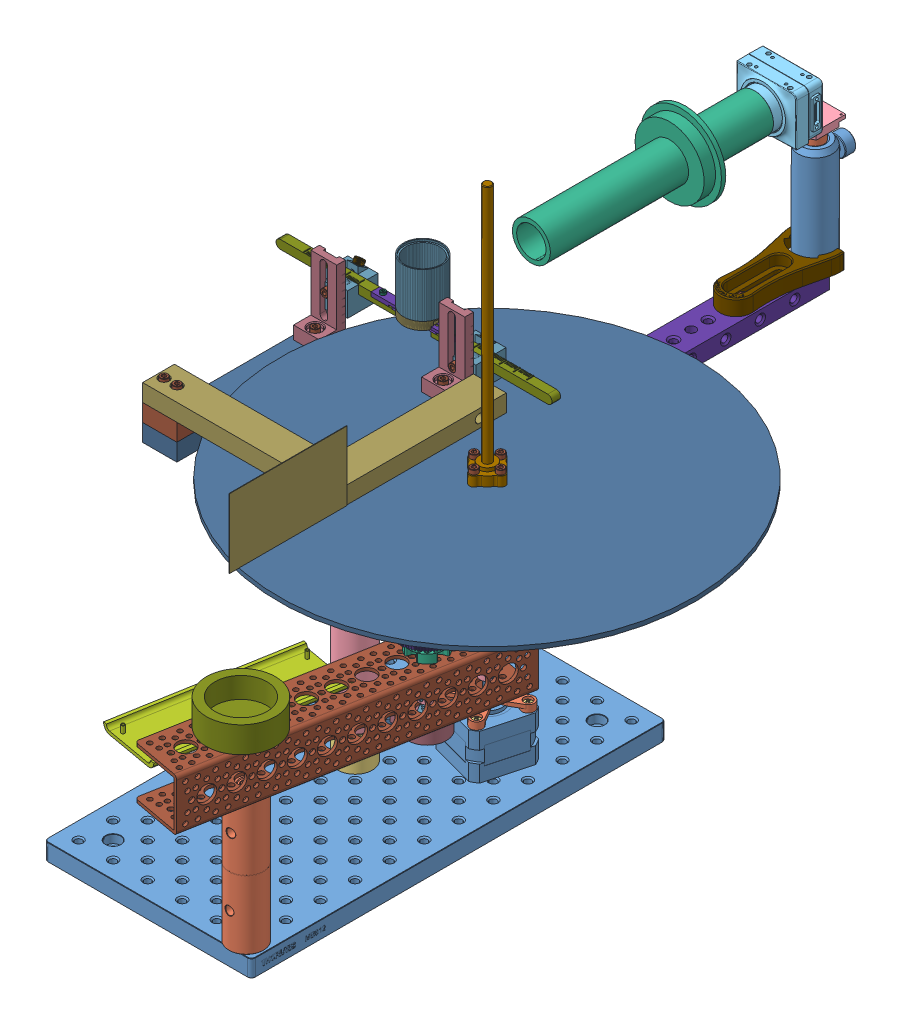
SolidWorks assembly Treadmill Rig, configuration Default. Lengths in mm.
Overall size (431.05 433.26 578.18).
98 component instances, 51 part files, 81 mates.
Components (placement in the parent):
- THORLABS_baseplate_MB612-1: THORLABS_baseplate_MB612 [Default] at (-0.1242 -6.1137 192.459) x (0 0 -1) z (1 0 0) size (304.8 12.7 152.4)
- THORLABS_RS2-1: THORLABS_RS2 [Default] at (59.6783 32.9835 335.1367) size (25.37 50.8 25.57)
- THORLABS_RS2-2: THORLABS_RS2 [Default] at (59.7309 82.7675 335.3233) x (0.99667 0 -0.081541) z (0.081541 0 0.99667) size (25.37 50.8 25.57)
- THORLABS_leg_RS1-1: THORLABS_leg_RS1 [Default] at (-12.6817 22.1402 176.1265) x (0.014723 0 0.999892) z (-0.999892 0 0.014723) size (25.57 25.4 25.37)
- THORLABS_leg_RS1-2: THORLABS_leg_RS1 [Default] at (-64.1349 22.3942 132.5582) x (0.086893 0 -0.996218) z (0.996218 0 0.086893) size (25.57 25.4 25.37)
- THORLABS_leg_RS6-1: THORLABS_leg_RS6 [Default] at (-12.2453 109.5652 178.3441) size (25.37 152.4 25.57)
- THORLABS_leg_RS6-2: THORLABS_leg_RS6 [Default] at (-63.0453 109.8192 127.5441) size (25.37 152.4 25.57)
- gonio_platform-1: gonio_platform [Default] at (-38.5742 174.1917 156.509) x (0 0 -1) z (1 0 0) size (97.5 10 97.5)
- GOH-40A35RUU-1: GOH-40A35RUU [Default] at (-4.8242 205.9417 127.759) x (-1 0 0) z (0 1 0) size (50.47 46.7 16)
  - GOH40A35RUU-M02-13001-S02-1: GOH40A35RUU-M02-13001-S02 [Default] at origin size (50 40 13.5)
  - GOH40A35RUU-M02-13001-S01-1: GOH40A35RUU-M02-13001-S01 [Default] at origin size (40.85 46.7 14)
- GOH-40A51UU-1: GOH-40A51UU [Default] at (-9.8242 133.1917 127.759) x (0 0 -1) z (0 -1 0) size (50.27 46.7 15)
  - GOH-8UU-C1B-S02-1: GOH-8UU-C1B-S02 [Default] at origin size (50 40 12.5)
  - GOH-8UU-C1B-S01-1: GOH-8UU-C1B-S01 [Default] x (0 1 0) z (0 0 1) size (46.7 40.57 13)
- headbar platform-1: headbar platform [Default] at (-72.0542 215.1917 200.699) size (93.98 12.7 156.21)
- Cap spacer-1: Cap spacer [Default] at (-72.0542 227.8917 252.769) size (25.4 12.7 22.86)
- headbar platform 2-1: headbar platform 2 [Default] at (-8.3145 240.5917 253.531) x (0 0 1) z (-1 0 0) size (127 12.7 140.21)
- headbar_post-1: headbar_post [Default] at (-81.5792 227.8917 156.249) x (0 0 -1) z (1 0 0) size (19.05 50.8 19.07)
- headbar_post-2: headbar_post [Default] at (12.5135 241.8617 156.249) x (0 0 -1) z (1 0 0) size (19.05 50.8 19.07)
- headbar finished flipped (1)-1: headbar finished flipped (1) [Default] at (-60.8105 251.2717 126.0865) x (-1 0 0) z (0 0 -1) size (88.9 24.86 25.74)
  - bar rest-1: bar rest [Default] at origin size (22.23 22.61 24.77)
  - 91292A003_TYPE 18-8 SS SOCKET HEAD CAP SCREW-1: 91292A003_TYPE 18-8 SS SOCKET HEAD CAP SCREW [91292A003] at (-14.8888 5.7455 0) x (1 0 0) z (0 -1 0) size (3.8 3.8 5.09)
  - headbar-1: headbar [Default] at (-76.8022 -57.3797 49.0764) x (0 0 -1) z (1 0 0) size (6.4 6.86 88.9)
    - headpost holder-1: headpost holder [Default] at (49.0764 62.9677 48.5529) x (0 1 0) z (0 0 1) size (6.86 6.35 88.9)
    - headbar clamp-1: headbar clamp [Default] at (49.0764 64.2202 58.1033) x (0 0 1) z (-1 0 0) size (19.1 3.05 6.4)
  - 96125A301_NICKEL ALLOY SHOULDER SCREW-1: 96125A301_NICKEL ALLOY SHOULDER SCREW [96125A301] at (10.7798 13.9746 8.8593) x (0.978373 0.111501 -0.174221) z (0 0.842271 0.539054) size (6.35 6.35 10.69)
- headbar finished assem (1)-1: headbar finished assem (1) [Default] at (33.2821 251.0177 126.0865) x (-1 0 0) z (0 0 -1) size (88.9 24.55 25.25)
  - bar rest-1: bar rest [Default] at origin size (22.23 22.61 24.77)
  - 91292A003_TYPE 18-8 SS SOCKET HEAD CAP SCREW-1: 91292A003_TYPE 18-8 SS SOCKET HEAD CAP SCREW [91292A003] at (27.4332 5.7455 0) x (1 0 0) z (0 -1 0) size (3.8 3.8 5.09)
  - headbar-1: headbar [Default] at (89.3465 -57.3797 -49.0764) x (0 0 1) z (-1 0 0) size (6.4 6.86 88.9)
    - headpost holder-1: headpost holder [Default] at (49.0764 62.9677 48.5529) x (0 1 0) z (0 0 1) size (6.86 6.35 88.9)
    - headbar clamp-1: headbar clamp [Default] at (49.0764 64.2202 58.1033) x (0 0 1) z (-1 0 0) size (19.1 3.05 6.4)
  - 96125A301_NICKEL ALLOY SHOULDER SCREW-1: 96125A301_NICKEL ALLOY SHOULDER SCREW [96125A301] at (10.7798 13.9746 8.8593) x (1 0 0) z (0 0.842271 0.539054) size (6.35 6.35 10.69)
- Round Screw Plate (1)-2: Round Screw Plate (1) [Default] at (63.3758 107.2225 332.159) size (25.39 5.58 25.39) (hidden)
- 6-32 Screw-1: 6-32 Screw [Default] at (63.3758 102.3127 332.159) x (0 0 1) z (0 -1 0) size (5.74 5.74 13.19) (hidden)
- Stepper Motor assem-1: Stepper Motor assem [Default] at (89.2983 64.2757 184.6539) x (0.258819 0 -0.965926) z (0.965926 0 0.258819) size (46.31 68.68 42)
  - Stepper Motor 9328-1: Stepper Motor 9328 [Default] at origin size (46.31 57.25 42)
  - 555152 assembly-1: 555152 assembly [Default] at (-46.3202 49.2232 -16.8805) x (-1 0 0) z (0 0 1) size (40.13 13.81 40.13)
    - 555152-1: 555152 [Default] at (-46.3202 6.3172 16.8805) size (40.13 10.02 40.13)
    - 555152 screw_92005A116-1: 555152 screw_92005A116 [Default] at (-61.8202 19.9372 32.3805) x (1 0 0) z (0 -1 0) size (6 6 8.48)
    - 555152 screw_92005A116-2: 555152 screw_92005A116 [Default] at (-30.8202 19.9372 32.3805) x (0 0 -1) z (0 -1 0) size (6 6 8.48)
    - 555152 screw_92005A116-3: 555152 screw_92005A116 [Default] at (-30.8202 19.9372 1.3805) x (-1 0 0) z (0 -1 0) size (6 6 8.48)
    - 555152 screw_92005A116-4: 555152 screw_92005A116 [Default] at (-61.8202 19.9372 1.3805) x (0 0 1) z (0 -1 0) size (6 6 8.48)
  - Motor coupler-1: Motor coupler [Default] at (-58.4931 67.3592 -25.2523) x (-1 0 0) z (0 0 1) size (10.67 19.11 10.81)
    - 625120-1: 625120 [Default] at (-58.4931 -1.3175 25.2523) size (10.67 19.05 10.73)
    - 632134_91375A436-1: 632134_91375A436 [Default] at (-58.4931 14.3035 29.3961) x (0.606109 -0.795381 0) z (0 0 1) size (4.98 4.83 3.31)
    - 632134_91375A436-2: 632134_91375A436 [Default] at (-58.4931 2.1115 29.3961) x (0.605824 -0.795599 0) z (0 0 1) size (4.98 4.83 3.31)
- Dual Ball Bearing Hub-1: Dual Ball Bearing Hub [Default] at (119.3156 154.9729 164.5547) size (25.4 12.82 25.4)
  - 545444-1: 545444 [Default] at (-30.0172 -12.6196 20.0992) size (25.4 12.82 25.4)
  - 535020-1: 535020 [Default] at (-30.0172 -2.3009 20.0992) size (12.7 4.76 12.7)
  - 535020-2: 535020 [Default] at (-30.0172 -10.2384 20.0992) x (-0.612569 0 0.790417) z (-0.790417 0 -0.612569) size (12.7 4.76 12.7)
- Dual Ball Bearing Hub-2: Dual Ball Bearing Hub [Default] at (112.4883 158.1291 202.038) size (25.4 12.82 25.4)
  - 545444-1: 545444 [Default] at (-30.0172 -12.6196 20.0992) size (25.4 12.82 25.4)
  - 535020-1: 535020 [Default] at (-30.0172 -2.3009 20.0992) size (12.7 4.76 12.7)
  - 535020-2: 535020 [Default] at (-30.0172 -10.2384 20.0992) x (-0.612569 0 0.790417) z (-0.790417 0 -0.612569) size (12.7 4.76 12.7)
- 48 Pitch 72T Gear-1: 48 Pitch 72T Gear [Default] at (89.2983 155.0533 184.6539) x (1 0 0) z (0 1 0) size (39.16 39.16 9.53)
- 48 Pitch 72T Gear-2: 48 Pitch 72T Gear [Default] at (82.471 158.2094 222.1372) x (1 0 0) z (0 1 0) size (39.16 39.16 9.53)
- 12in shaft sldprt-2: 12in shaft sldprt [Default] at (89.2983 122.3502 184.6539) size (6.34 304.8 6.34)
- Track-1: Track [Default] at (89.5764 237.3058 185.33) x (-0.707107 0 -0.707107) z (0.707107 0 -0.707107) size (304.8 3.17 304.8)
- Aluminum Channel 585450-4: Aluminum Channel 585450 [Default] at (111.4536 107.1817 169.3259) x (0 1 0) z (-0.179194 0 0.983814) size (38.1 38.1 228.6)
- plastic sheet-1: plastic sheet [Default] at (56.0745 265.7822 297.7239) x (0 0 1) z (-1 0 0) size (86.36 50.8 0.76)
- Encoder-1: Encoder [Default] at (67.0944 107.1817 222.1372) x (0 0 -1) z (0 -1 0) size (28.19 32.65 25.88)
  - encoder body-1: encoder body [Default] at origin size (28.19 32.65 12.29)
  - 92620A401_HIGH-STRENGTH GRADE 8 STEEL CAP SCREW-1: 92620A401_HIGH-STRENGTH GRADE 8 STEEL CAP SCREW [92620A401] at (0.0022 15.3756 -3.9688) x (0 0 -1) z (1 0 0) size (16.31 11 9.53)
- Motor coupler-1: Motor coupler [Default] at (140.9641 115.6246 196.8849) size (10.67 19.11 10.81)
  - 625120-1: 625120 [Default] at (-58.4931 -1.3175 25.2523) size (10.67 19.05 10.73)
  - 632134_91375A436-1: 632134_91375A436 [Default] at (-58.4931 14.3035 29.3961) x (0.606109 -0.795381 0) z (0 0 1) size (4.98 4.83 3.31)
  - 632134_91375A436-2: 632134_91375A436 [Default] at (-58.4931 2.1115 29.3961) x (0.605824 -0.795599 0) z (0 0 1) size (4.98 4.83 3.31)
- 2in shaft sldprt-1: 2in shaft sldprt [Default] at (82.471 127.4545 222.1372) size (6.34 50.8 6.34)
- weighing dish-1: weighing dish [Default] at (62.5051 145.2817 338.978) size (50.8 19.05 50.8)
- horizontal support 12in-1: horizontal support 12in [Default] at (-8.8742 148.3921 0.2787) x (0 0 -1) z (1 0 0) size (304.8 12.7 25.4)
- CF125-Solidworks-1: CF125-Solidworks [Default] at (-8.8742 166.8071 -154.411) size (36.32 12.6 73.79)
- PH3-Solidworks-2: PH3-Solidworks [Default] at (-8.8742 199.1921 -154.411) x (-1 0 0) z (0 0 -1) size (25 76.81 35.41)
- 0.5in shaft-1: 0.5in shaft [Default] at (-8.8742 168.4097 -154.411) size (12.69 76.2 12.69)
- 90322A645_HIGH-STRENGTH STEEL THREADED ROD-1: 90322A645_HIGH-STRENGTH STEEL THREADED ROD [90322A645] at (-8.8742 239.8472 -154.411) x (0 1 0) z (0 0 1) size (26.4 6.43 6.7)
- camera adapter-3: camera adapter [Default] at (-8.8742 250.3247 -154.411) x (0 0 1) z (1 0 0) size (26.9 5.71 17.9)
- cm3-u3-13y3m-cs camera-2: cm3-u3-13y3m-cs camera [Default] at (-16.4673 268.3484 -131.7476) size (45.85 36.05 28.67)
- 20x lense body-1: 20x lense body [Default] at (-16.4673 268.3484 -117.3347) size (59.44 59.44 163.96)
- electronics tray-1: electronics tray [Default] at (64.2218 135.5171 263.4225) x (0.984808 0 0.173648) z (-0.173648 0 0.984808) size (45.53 7.48 127)
- visual cortex headpost-4: visual cortex headpost [Default] at (-58.3763 256.6582 107.5862) x (-1 0 0) z (0 0 -1) size (32.4 1.2 14.66)
- Treadmill clamp 545548-3: Treadmill clamp 545548 [Default] at (68.1274 262.7131 150.7962) x (-0.707107 0 -0.707107) z (-0.707107 0 0.707107) size (21.08 13.19 21.37)
  - 545548-1: 545548 [Default] at (-38.9112 12.0765 8.9709) size (20.57 9.63 20.57)
  - 632138_91375A438-1: 632138_91375A438 [Default] at (-38.9112 18.109 15.0823) x (0.93363 0.358238 0) z (0 0 1) size (4.98 4.83 6.49)
  - 6-32 Screw-1: 6-32 Screw [Default] at (-45.6425 24.1415 15.9952) x (-0.707107 0 -0.707107) z (0 1 0) size (5.74 5.74 13.19)
- 6-32 Screw-3: 6-32 Screw [Default] at (89.2983 238.5716 174.8749) x (1 0 0) z (0 -1 0) size (5.74 5.74 13.19)
- 6-32 Screw-4: 6-32 Screw [Default] at (79.5193 238.5716 184.6539) x (1 0 0) z (0 -1 0) size (5.74 5.74 13.19)
- 6-32 Screw-5: 6-32 Screw [Default] at (99.0773 238.5716 184.6539) x (1 0 0) z (0 -1 0) size (5.74 5.74 13.19)
- 6-32 Screw-6: 6-32 Screw [Default] at (-72.0542 225.2247 149.899) x (0 0 -1) z (0 -1 0) size (5.74 5.74 13.19)
- 6-32 Screw-7: 6-32 Screw [Default] at (22.0385 239.1947 149.899) x (0 0 -1) z (0 -1 0) size (5.74 5.74 13.19)
- 6-32 Screw-8: 6-32 Screw [Default] at (-72.0542 255.7167 130.214) x (1 0 0) z (0 0 -1) size (5.74 5.74 13.19)
- 6-32 Screw-9: 6-32 Screw [Default] at (22.0385 255.4627 130.214) x (1 0 0) z (0 0 -1) size (5.74 5.74 13.19)
- 6-32 Screw-10: 6-32 Screw [Default] at (-79.4345 241.7855 253.531) x (0 0 -1) z (0 -1 0) size (5.74 5.74 13.19)
- 6-32 Screw-11: 6-32 Screw [Default] at (-69.8754 241.7855 253.531) x (0 0 1) z (0 -1 0) size (5.74 5.74 13.19)
- 6-32 Screw-12: 6-32 Screw [Default] at (-8.8742 162.9971 114.5787) x (-1 0 0) z (0 1 0) size (5.74 5.74 13.19)
- 6-32 Screw-14: 6-32 Screw [Default] at (-8.8742 151.5671 -101.071) x (1 0 0) z (0 -1 0) size (5.74 5.74 13.19)
- light proofing-crown-1: light proofing-crown [Default] at (-78.0808 257.7606 174.7655) x (1 0 0) z (0 1 0) size (27.95 27.95 6.18)
- Gonio Square-1: Gonio Square [Default] at (-9.3822 161.4917 127.317) size (39.12 12.7 39.12)
- light proofing-cylinder-1: light proofing-cylinder [Default] at (-103.1867 263.6589 169.4307) x (1 0 0) z (0 1 0) size (28.2 28.2 33)
Mates (geometry in assembly coordinates):
- Concentric5: concentric aligned: circle of THORLABS_baseplate_MB612-1; circle of THORLABS_leg_RS1-1
- Coincident2: coincident aligned: plane of THORLABS_baseplate_MB612-1 through (73.0758 6.5863 341.859) normal (0 1 0); circle of THORLABS_leg_RS1-1
- Lock5: lock: unknown of THORLABS_baseplate_MB612-1; unknown of THORLABS_leg_RS1-2
- Concentric8: concentric anti-aligned: circle of THORLABS_leg_RS1-1; circle of THORLABS_leg_RS6-1
- Concentric9: concentric anti-aligned: circle of THORLABS_leg_RS1-2; circle of THORLABS_leg_RS6-2
- Coincident5: coincident anti-aligned: plane of THORLABS_baseplate_MB612-1 through (73.0758 6.5863 341.859) normal (0 1 0); plane of THORLABS_leg_RS1-2 through (-63.6242 6.5863 128.959) normal (0 -1 0)
- Coincident6: coincident anti-aligned: plane of THORLABS_leg_RS1-2 through (-63.6242 31.9863 128.959) normal (0 1 0); plane of THORLABS_leg_RS6-2 through (-63.6242 31.9863 128.959) normal (0 -1 0)
- Coincident7: coincident anti-aligned: plane of THORLABS_leg_RS1-1 through (-12.8242 31.7323 179.759) normal (0 1 0); plane of THORLABS_leg_RS6-1 through (-12.8242 31.7323 179.759) normal (0 -1 0)
- Coincident8: coincident anti-aligned: circle of THORLABS_RS2-1; circle of THORLABS_RS2-2
- Concentric10: concentric aligned: circle of THORLABS_leg_RS6-1; circle of gonio_platform-1
- Lock7: lock: unknown of THORLABS_leg_RS6-2; unknown of gonio_platform-1
- Lock8: lock: unknown of THORLABS_leg_RS6-1; unknown of gonio_platform-1
- Coincident9: coincident anti-aligned: plane of gonio_platform-1 through (-38.5742 184.1917 156.509) normal (0 1 0); plane of GOH-40A51UU-1/GOH-8UU-C1B-S01-1 through (-9.8242 184.1917 65.759) normal (0 -1 0)
- Coincident10: coincident aligned: plane of gonio_platform-1 through (-87.3242 184.1917 107.759) normal (0 0 -1); plane of GOH-40A51UU-1/GOH-8UU-C1B-S01-1 through (-9.8242 195.1917 107.759) normal (0 0 -1)
- Coincident11: coincident aligned: plane of gonio_platform-1 through (10.1758 184.1917 205.259) normal (1 0 0); plane of GOH-40A51UU-1/GOH-8UU-C1B-S01-1 through (10.1758 133.1917 96.759) normal (1 0 0)
- Coincident12: coincident anti-aligned: plane of GOH-40A35RUU-1/GOH40A35RUU-M02-13001-S02-1 through (-19.8242 199.1917 117.759) normal (0 -1 0); plane of GOH-40A51UU-1/GOH-8UU-C1B-S02-1 through (-19.8242 199.1917 137.759) normal (0 1 0)
- Coincident14: coincident aligned: plane of GOH-40A35RUU-1/GOH40A35RUU-M02-13001-S02-1 through (-29.8242 250.1917 107.759) normal (-1 0 0); plane of GOH-40A51UU-1/GOH-8UU-C1B-S01-1 through (-29.8242 133.1917 96.759) normal (-1 0 0)
- Coincident15: coincident aligned: plane of GOH-40A35RUU-1/GOH40A35RUU-M02-13001-S01-1 through (-33.3242 250.1917 107.759) normal (0 0 -1); plane of GOH-40A51UU-1/GOH-8UU-C1B-S02-1 through (-9.8242 133.1917 107.759) normal (0 0 -1)
- Coincident16: coincident anti-aligned: plane of GOH-40A35RUU-1/GOH40A35RUU-M02-13001-S01-1 through (-56.8242 215.1917 127.759) normal (0 1 0); plane of headbar platform-1 through (-72.0542 215.1917 200.699) normal (0 -1 0)
- Concentric11: concentric aligned: circle of GOH-40A35RUU-1/GOH40A35RUU-M02-13001-S01-1; circle of headbar platform-1
- Concentric13: concentric aligned: circle of headbar platform-1; circle of Cap spacer-1
- Coincident30: coincident anti-aligned: plane of Cap spacer-1 through (-72.0542 240.5917 252.769) normal (0 1 0); plane of headbar platform 2-1 through (-8.3145 240.5917 253.531) normal (0 -1 0)
- Coincident31: coincident aligned: plane of Cap spacer-1 through (-84.7542 240.5917 264.199) normal (0 0 1); plane of headbar platform 2-1 through (55.6935 253.2917 264.199) normal (0 0 1)
- Concentric16: concentric aligned: circle of headbar platform-1; circle of headbar_post-1
- Coincident32: coincident anti-aligned: plane of headbar platform-1 through (-72.0542 227.8917 200.699) normal (0 1 0); plane of headbar_post-1 through (-62.5292 227.8917 156.249) normal (0 -1 0)
- Coincident34: coincident aligned: plane of headbar platform 2-1 through (55.6935 253.2917 137.199) normal (0 0 -1); plane of headbar_post-2 through (31.5635 241.8617 137.199) normal (0 0 -1)
- Concentric19: concentric anti-aligned: circle of headbar_post-2; circle of headbar finished assem (1)-1/bar rest-1
- Coincident42: coincident anti-aligned: plane of headbar_post-2 through (31.5635 241.8617 137.199) normal (0 0 -1); plane of headbar finished assem (1)-1/bar rest-1 through (11.0571 259.7807 137.199) normal (0 0 1)
- Coincident43: coincident anti-aligned: plane of headbar_post-1 through (-62.5292 227.8917 137.199) normal (0 0 -1); plane of headbar finished flipped (1)-1/bar rest-1 through (-83.0355 260.0347 137.199) normal (0 0 1)
- Concentric21: concentric anti-aligned: circle of Round Screw Plate (1)-2; circle of 6-32 Screw-1
- Coincident47: coincident aligned: cone of Round Screw Plate (1)-2 through (63.3758 112.4295 332.159) axis (0 -1 0); cone of 6-32 Screw-1 through (63.3758 111.8377 332.159) axis (0 -1 0)
- Concentric29: concentric anti-aligned: circle of Dual Ball Bearing Hub-1/535020-1; circle of 48 Pitch 72T Gear-1
- Coincident54: coincident anti-aligned: plane of Dual Ball Bearing Hub-1/545444-1 through (89.2983 155.0533 184.6539) normal (0 1 0); plane of 48 Pitch 72T Gear-1 through (89.2983 155.0533 184.6539) normal (0 -1 0)
- Concentric30: concentric anti-aligned: circle of Dual Ball Bearing Hub-2/535020-1; circle of 48 Pitch 72T Gear-2
- Coincident55: coincident anti-aligned: plane of Dual Ball Bearing Hub-2/545444-1 through (82.471 158.2094 222.1372) normal (0 1 0); plane of 48 Pitch 72T Gear-2 through (82.471 158.2094 222.1372) normal (0 -1 0)
- Lock10: lock: unknown of Stepper Motor assem-1/Motor coupler-1/625120-1; unknown of 12in shaft sldprt-2
- Concentric36: concentric aligned: cylinder of 48 Pitch 72T Gear-1 through (89.2983 155.0523 184.6539) axis (0 1 0) radius 1.5875; cylinder of 12in shaft sldprt-2 through (89.2983 122.3502 184.6539) axis (0 1 0) radius 3.1712
- Lock9: lock: unknown of THORLABS_RS2-2; unknown of Aluminum Channel 585450-4
- Concentric40: concentric anti-aligned: circle of Stepper Motor assem-1/555152 assembly-1/555152-1; circle of Aluminum Channel 585450-4
- Lock11: lock: unknown of Stepper Motor assem-1/555152 assembly-1/555152-1; unknown of Aluminum Channel 585450-4
- Concentric41: concentric aligned: circle of Dual Ball Bearing Hub-2/535020-2; circle of Aluminum Channel 585450-4
- Coincident68: coincident anti-aligned: plane of headbar platform 2-1 through (55.6935 253.2917 264.199) normal (1 0 0); plane of plastic sheet-1 through (55.6935 265.7822 297.7239) normal (-1 0 0)
- Concentric43: concentric aligned: circle of Aluminum Channel 585450-4; circle of Encoder-1/92620A401_HIGH-STRENGTH GRADE 8 STEEL CAP SCREW-1
- Coincident69: coincident anti-aligned: plane of Aluminum Channel 585450-4 through (70.4898 107.1817 394.2257) normal (0 -1 0); plane of Encoder-1/encoder body-1 through (82.471 107.1817 222.1372) normal (0 1 0)
- Concentric44: concentric anti-aligned: circle of Encoder-1/92620A401_HIGH-STRENGTH GRADE 8 STEEL CAP SCREW-1; circle of Motor coupler-1/625120-1
- Concentric45: concentric aligned: circle of 48 Pitch 72T Gear-2; circle of 2in shaft sldprt-1
- Coincident70: coincident anti-aligned: plane of Aluminum Channel 585450-4 through (33.0065 145.2817 387.3984) normal (0 1 0); plane of weighing dish-1 through (62.5051 145.2817 338.978) normal (0 -1 0)
- Concentric49: concentric aligned: circle of CF125-Solidworks-1; circle of PH3-Solidworks-2
- Concentric50: concentric aligned: circle of PH3-Solidworks-2; circle of 0.5in shaft-1
- Concentric51: concentric anti-aligned: circle of 0.5in shaft-1; circle of 90322A645_HIGH-STRENGTH STEEL THREADED ROD-1
- Concentric56: concentric anti-aligned: circle of 90322A645_HIGH-STRENGTH STEEL THREADED ROD-1; circle of camera adapter-3
- Coincident82: coincident anti-aligned: plane of 0.5in shaft-1 through (-8.8742 244.6097 -154.411) normal (0 1 0); plane of camera adapter-3 through (0.5961 244.6097 -167.3407) normal (0 -1 0)
- Concentric60: concentric aligned: circle of camera adapter-3; circle of cm3-u3-13y3m-cs camera-2
- Concentric62: concentric anti-aligned: circle of cm3-u3-13y3m-cs camera-2; circle of 20x lense body-1
- Coincident87: coincident anti-aligned: circle of Aluminum Channel 585450-4; plane of electronics tray-1 through (39.4956 142.9957 382.909) normal (0 1 0)
- Concentric69: concentric aligned: circle of Aluminum Channel 585450-4; circle of electronics tray-1
- Lock14: lock: unknown of THORLABS_baseplate_MB612-1; unknown of THORLABS_RS2-1
- Concentric75: concentric anti-aligned: circle of 12in shaft sldprt-2; circle of Treadmill clamp 545548-3/545548-1
- Concentric78: concentric aligned: circle of Treadmill clamp 545548-3/545548-1; circle of 6-32 Screw-4
- Coincident90: coincident anti-aligned: plane of Treadmill clamp 545548-3/545548-1 through (94.1878 248.0966 184.6539) normal (0 1 0); plane of 6-32 Screw-4 through (79.5193 248.0966 184.6539) normal (0 -1 0)
- Concentric79: concentric anti-aligned: circle of Treadmill clamp 545548-3/545548-1; circle of 6-32 Screw-5
- Coincident91: coincident anti-aligned: plane of Treadmill clamp 545548-3/545548-1 through (94.1878 248.0966 184.6539) normal (0 1 0); plane of 6-32 Screw-5 through (99.0773 248.0966 184.6539) normal (0 -1 0)
- Concentric80: concentric aligned: circle of Treadmill clamp 545548-3/545548-1; circle of 6-32 Screw-3
- Coincident92: coincident anti-aligned: plane of Treadmill clamp 545548-3/545548-1 through (94.1878 248.0966 184.6539) normal (0 1 0); plane of 6-32 Screw-3 through (89.2983 248.0966 174.8749) normal (0 -1 0)
- Concentric81: concentric aligned: circle of headbar_post-2; circle of 6-32 Screw-7
- Coincident94: coincident anti-aligned: plane of headbar_post-2 through (22.0385 248.7197 145.1365) normal (0 1 0); plane of 6-32 Screw-7 through (22.0385 248.7197 149.899) normal (0 -1 0)
- Concentric82: concentric aligned: circle of headbar_post-1; circle of 6-32 Screw-6
- Coincident95: coincident anti-aligned: plane of headbar_post-1 through (-72.0542 234.7497 145.1365) normal (0 1 0); plane of 6-32 Screw-6 through (-72.0542 234.7497 149.899) normal (0 -1 0)
- Concentric83: concentric aligned: circle of headbar finished flipped (1)-1/bar rest-1; circle of 6-32 Screw-8
- Coincident96: coincident anti-aligned: plane of headbar finished flipped (1)-1/bar rest-1 through (-60.8105 251.2717 139.739) normal (0 0 1); plane of 6-32 Screw-8 through (-72.0542 255.7167 139.739) normal (0 0 -1)
- Concentric84: concentric aligned: circle of headbar finished assem (1)-1/bar rest-1; circle of 6-32 Screw-9
- Coincident97: coincident anti-aligned: plane of headbar finished assem (1)-1/bar rest-1 through (33.2821 251.0177 139.739) normal (0 0 1); plane of 6-32 Screw-9 through (22.0385 255.4627 139.739) normal (0 0 -1)
- Concentric85: concentric aligned: circle of headbar platform 2-1; circle of 6-32 Screw-10
- Coincident98: coincident anti-aligned: plane of headbar platform 2-1 through (-79.4345 251.3105 255.2582) normal (0 1 0); plane of 6-32 Screw-10 through (-79.4345 251.3105 253.531) normal (0 -1 0)
- Concentric87: concentric aligned: circle of headbar platform 2-1; circle of 6-32 Screw-11
- Coincident99: coincident anti-aligned: plane of headbar platform 2-1 through (-69.8754 251.3105 255.2582) normal (0 1 0); plane of 6-32 Screw-11 through (-69.8754 251.3105 253.531) normal (0 -1 0)
- Concentric88: concentric anti-aligned: circle of horizontal support 12in-1; circle of 6-32 Screw-12
- Concentric89: concentric anti-aligned: circle of horizontal support 12in-1; circle of 6-32 Screw-14
- Coincident100: coincident anti-aligned: plane of gonio_platform-1 through (-38.5742 174.1917 156.509) normal (0 -1 0); plane of Gonio Square-1 through (-9.3822 174.1917 127.317) normal (0 1 0)
- Coincident101: coincident aligned: plane of gonio_platform-1 through (10.1758 184.1917 205.259) normal (1 0 0); plane of Gonio Square-1 through (10.1758 174.1917 107.759) normal (1 0 0)
- Coincident102: coincident aligned: plane of gonio_platform-1 through (-87.3242 184.1917 107.759) normal (0 0 -1); plane of Gonio Square-1 through (-28.9402 174.1917 107.759) normal (0 0 -1)
